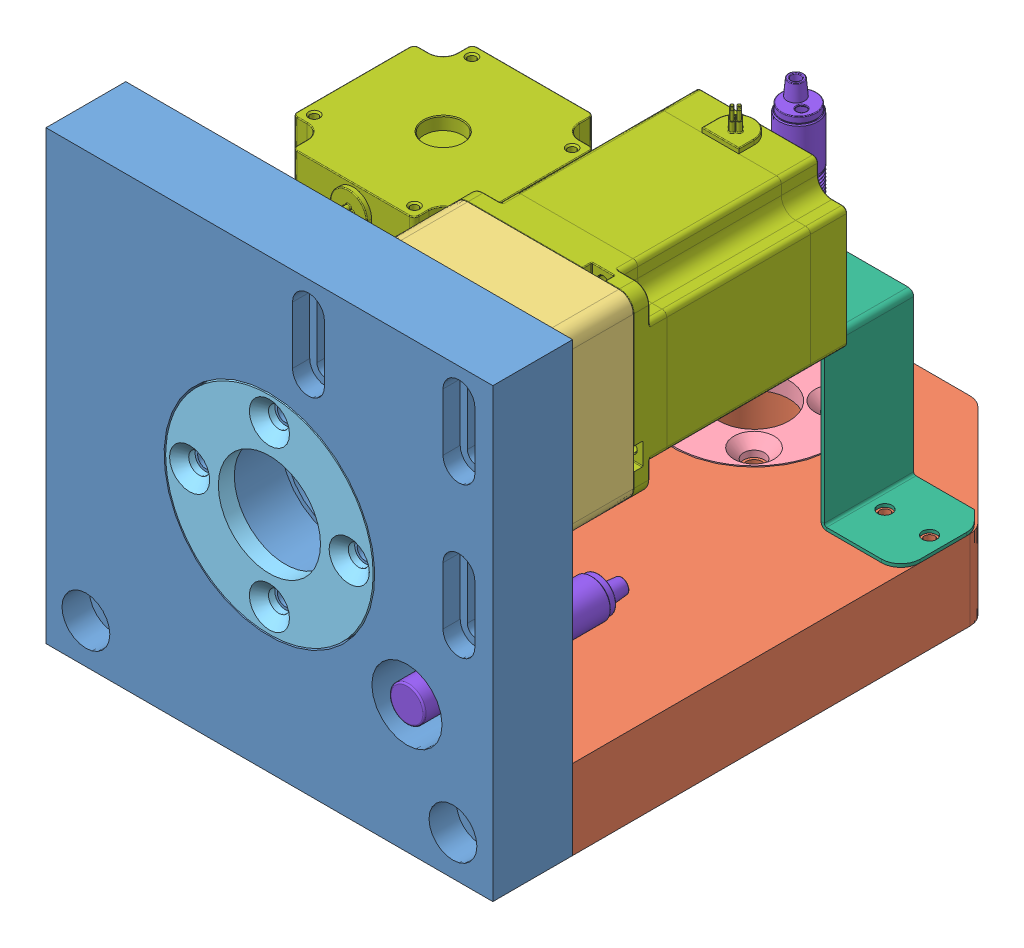
SolidWorks assembly C Axis, configuration Défaut. Lengths in mm.
Overall size (140 143.41 187).
13 component instances, 9 part files, 37 mates.
Components (placement in the parent):
- Top v-2-1: Top v-2 [Défaut] at (0 0 151.83) x (0 -1 0) z (0 0 -1) size (140 140 25)
- Right Main v-2-1: Right Main v-2 [Défaut] at (0 -45 45.83) x (1 0 0) z (0 -1 0) size (140 162 25)
- Nema 23 Mount C Axis v-2-1: Nema 23 Mount C Axis v-2 [Défaut] at (-29.77 -45 67.6154) x (1 0 0) z (0 1 0) size (56.4 56.4 25)
- Nema 23 Mount C Axis v-2-2: Nema 23 Mount C Axis v-2 [Défaut] at (35.8 37.7142 126.83) x (0 -1 0) z (0 0 -1) size (56.4 56.4 25)
- Couvercle B Axis-1: Couvercle B Axis [Défaut] at (0 -50 0) x (1 0 0) z (0 1 0) size (50 50 5)
- couvercle Roullement C axis v-2-1: couvercle Roullement C axis v-2 [Défaut] at (0 0 151.83) x (-1 0 0) z (0 0 -1) size (65 65 5)
- Tole Pliée-1: Tole Pliée [Défaut] at (45 -14.7619 24) size (55 51 28)
- NEMA23 Stepper Motor-1: NEMA23 Stepper Motor [57BYGH502] at (35.8 37.7142 101.83) size (56.69 64.04 88)
- NEMA23 Stepper Motor-2: NEMA23 Stepper Motor [57BYGH502] at (-29.77 -20 67.6154) x (1 0 0) z (0 -1 0) size (56.69 64.04 88)
- Rod Inductif Sensor-1: Rod Inductif Sensor [Défaut] at (49.7036 -43.6768 133.0622) x (-0.923728 -0.383049 0) z (0 0 -1) size (12.8 13.04 65)
- Rod Inductif Sensor-2: Rod Inductif Sensor [Défaut] at (15.5392 11.7678 22.6208) x (0.861332 0 0.508042) z (0 1 0) size (12.8 13.04 65)
- pulley_p27t5122fa-1: pulley_p27t5122fa [Default] at (35.8 37.7142 104.93) x (0 0 1) z (-0.999057 0.043409 0) size (21 23.68 23.68)
- pulley_p27t5122fa-2: pulley_p27t5122fa [Default] at (-29.77 -23.1 67.6154) x (0 -1 0) z (0.118939 0 0.992902) size (21 23.68 23.68)
Mates (geometry in assembly coordinates):
- Coïncidente1: coincident anti-aligned: plane of Top v-2-1 through (0 0 126.83) normal (0 0 -1); plane of Right Main v-2-1 through (70 -70 126.83) normal (0 0 1)
- Coïncidente2: coincident aligned: plane of Top v-2-1 through (-70 -70 126.83) normal (0 -1 0); plane of Right Main v-2-1 through (0 -70 45.83) normal (0 -1 0)
- Coïncidente3: coincident aligned: plane of Top v-2-1 through (-70 70 126.83) normal (-1 0 0); plane of Right Main v-2-1 through (-70 -70 -35.17) normal (-1 0 0)
- Parallèle1: parallel aligned: plane of Top v-2-1 through (0 0 151.83) normal (0 0 1)
- Distance1: distance = 0 mm: cylinder of Right Main v-2-1 through (0 -103.9411 0) axis (0 1 0) radius 12
- Distance2: distance = 0 mm: cylinder of Right Main v-2-1 through (0 -103.9411 0) axis (0 1 0) radius 12
- Distance3: distance = 0 mm: cylinder of Top v-2-1 through (0 0 74.5041) axis (0 0 1) radius 18.5
- Coïncidente6: coincident anti-aligned: plane of Right Main v-2-1 through (0 -45 45.83) normal (0 1 0); plane of Nema 23 Mount C Axis v-2-1 through (-29.77 -45 67.6154) normal (0 -1 0)
- Coïncidente7: coincident anti-aligned: plane of Top v-2-1 through (0 0 126.83) normal (0 0 -1); plane of Nema 23 Mount C Axis v-2-2 through (35.8 37.7142 126.83) normal (0 0 1)
- Coaxiale1: concentric anti-aligned: cylinder of Top v-2-1 through (12.23 61.2842 151.83) axis (0 0 1) radius 2.75; cylinder of Nema 23 Mount C Axis v-2-2 through (12.23 61.2842 101.83) axis (0 0 -1) radius 2.1
- Coaxiale2: concentric anti-aligned: cylinder of Top v-2-1 through (59.37 61.2842 151.83) axis (0 0 1) radius 2.75; cylinder of Nema 23 Mount C Axis v-2-2 through (59.37 61.2842 101.83) axis (0 0 -1) radius 2.1
- Coaxiale3: concentric anti-aligned: cylinder of Right Main v-2-1 through (-6.2 -70 91.1854) axis (0 -1 0) radius 2.65; cylinder of Nema 23 Mount C Axis v-2-1 through (-6.2 -20 91.1854) axis (0 1 0) radius 2.1
- Parallèle2: parallel anti-aligned: cylinder of Right Main v-2-1 through (-53.37 -70 44.0454) axis (0 -1 0) radius 2.65; cylinder of Nema 23 Mount C Axis v-2-1 through (-53.34 -20 44.0454) axis (0 1 0) radius 2.1
- Coïncidente8: coincident anti-aligned: plane of Right Main v-2-1 through (0 -50 0) normal (0 1 0); plane of Couvercle B Axis-1 through (0 -50 0) normal (0 -1 0)
- Coaxiale5: concentric aligned: cylinder of Right Main v-2-1 through (0 -103.9411 0) axis (0 1 0) radius 12; cylinder of Couvercle B Axis-1 through (0 -50 0) axis (0 1 0) radius 11
- Coaxiale6: concentric aligned: cylinder of Right Main v-2-1 through (12.7279 -50 12.7279) axis (0 1 0) radius 2.5; cylinder of Couvercle B Axis-1 through (12.7279 -45 12.7279) axis (0 1 0) radius 3.3
- Coïncidente9: coincident anti-aligned: plane of Top v-2-1 through (0 0 146.83) normal (0 0 1); plane of couvercle Roullement C axis v-2-1 through (0 0 146.83) normal (0 0 -1)
- Coaxiale7: concentric aligned: cylinder of Top v-2-1 through (0 25 146.83) axis (0 0 1) radius 2.5; cylinder of couvercle Roullement C axis v-2-1 through (0 25 151.83) axis (0 0 1) radius 3.3
- Coaxiale8: concentric aligned: cylinder of Top v-2-1 through (-25 0 146.83) axis (0 0 1) radius 2.5; cylinder of couvercle Roullement C axis v-2-1 through (-25 0 151.83) axis (0 0 1) radius 3.3
- Coïncidente10: coincident anti-aligned: plane of Right Main v-2-1 through (0 -45 45.83) normal (0 1 0); plane of Tole Pliée-1 through (45 -45 -4) normal (0 -1 0)
- Coaxiale9: concentric anti-aligned: cylinder of Right Main v-2-1 through (51 -45 10) axis (0 1 0) radius 1.65; cylinder of Tole Pliée-1 through (51 -45 10) axis (0 -1 0) radius 2.25
- Coaxiale10: concentric anti-aligned: cylinder of Right Main v-2-1 through (65 -45 10) axis (0 1 0) radius 1.65; cylinder of Tole Pliée-1 through (65 -45 10) axis (0 -1 0) radius 2.25
- Coïncidente11: coincident anti-aligned: plane of Nema 23 Mount C Axis v-2-2 through (35.8 37.7142 101.83) normal (0 0 -1); plane of NEMA23 Stepper Motor-1 through (35.8 37.7142 101.83) normal (0 0 1)
- Coaxiale11: concentric anti-aligned: cylinder of Nema 23 Mount C Axis v-2-2 through (12.23 61.2842 101.83) axis (0 0 -1) radius 2.1; cylinder of NEMA23 Stepper Motor-1 through (12.23 61.2842 101.83) axis (0 0 1) radius 2.5
- Coaxiale12: concentric anti-aligned: cylinder of Nema 23 Mount C Axis v-2-2 through (59.37 61.2842 101.83) axis (0 0 -1) radius 2.1; cylinder of NEMA23 Stepper Motor-1 through (59.37 61.2842 101.83) axis (0 0 1) radius 2.5
- Coïncidente12: coincident anti-aligned: plane of Nema 23 Mount C Axis v-2-1 through (-29.77 -20 67.6154) normal (0 1 0); plane of NEMA23 Stepper Motor-2 through (-29.77 -20 67.6154) normal (0 -1 0)
- Coaxiale13: concentric anti-aligned: cylinder of Nema 23 Mount C Axis v-2-1 through (-53.34 -20 44.0454) axis (0 1 0) radius 2.1; cylinder of NEMA23 Stepper Motor-2 through (-53.34 -20 44.0454) axis (0 -1 0) radius 2.5
- Coaxiale14: concentric anti-aligned: cylinder of Nema 23 Mount C Axis v-2-1 through (-53.34 -20 91.1854) axis (0 1 0) radius 2.1; cylinder of NEMA23 Stepper Motor-2 through (-53.34 -20 91.1854) axis (0 -1 0) radius 2.5
- Coaxiale15: concentric aligned: cylinder of Top v-2-1 through (43.0842 -30 133.83) axis (0 0 1) radius 11; cylinder of Rod Inductif Sensor-1 through (43.0842 -30 151.83) axis (0 0 1) radius 5.5
- Coïncidente13: coincident aligned: plane of Top v-2-1 through (0 0 151.83) normal (0 0 1); plane of Rod Inductif Sensor-1 through (43.0842 -30 151.83) normal (0 0 1)
- Coaxiale16: concentric aligned: cylinder of Tole Pliée-1 through (24 15 10) axis (0 -1 0) radius 6; cylinder of Rod Inductif Sensor-2 through (24 -7 10) axis (0 -1 0) radius 5.5
- Distance4: distance = 12 mm aligned: plane of Rod Inductif Sensor-2 through (24 -7 10) normal (0 -1 0); plane of Tole Pliée-1 through (45 5 -4) normal (0 -1 0)
- Coaxiale17: concentric anti-aligned: cylinder of NEMA23 Stepper Motor-1 through (35.8 37.7142 122.83) axis (0 0 -1) radius 3.175; cylinder of pulley_p27t5122fa-1 through (35.8 37.7142 104.93) axis (0 0 1) radius 3.175
- Coaxiale18: concentric anti-aligned: cylinder of NEMA23 Stepper Motor-2 through (-29.77 -41 67.6154) axis (0 1 0) radius 3.175; cylinder of pulley_p27t5122fa-2 through (-29.77 -23.1 67.6154) axis (0 -1 0) radius 3.175
- Distance5: distance = 1.5 mm anti-aligned: plane of NEMA23 Stepper Motor-1 through (35.8 37.7142 103.43) normal (0 0 1); plane of pulley_p27t5122fa-1 through (35.8 37.7142 104.93) normal (0 0 -1)
- Parallèle3: parallel aligned: plane of Right Main v-2-1 through (-70 -70 -35.17) normal (-1 0 0); plane of Nema 23 Mount C Axis v-2-1 through (-57.97 -20 95.8154) normal (-1 0 0)
- Distance6: distance = 1.5 mm anti-aligned: plane of NEMA23 Stepper Motor-2 through (-29.77 -21.6 67.6154) normal (0 -1 0); plane of pulley_p27t5122fa-2 through (-29.77 -23.1 67.6154) normal (0 1 0)
